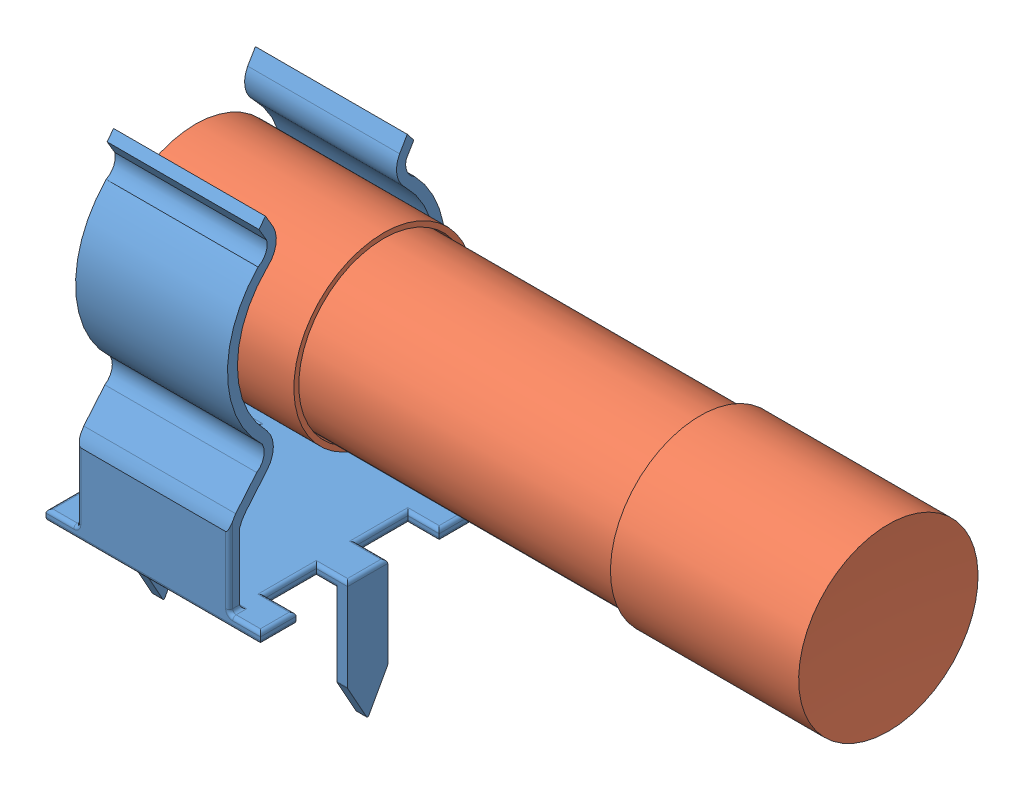
SolidWorks assembly SW3dPS-Full Fuse, configuration Default. Lengths in mm.
Overall size (21.01 12.9 6.2).
2 component instances, 2 part files, 3 mates.
Components (placement in the parent):
- SW3dPS-Full Fuse_Fuse Leg_2009-2: SW3dPS-Full Fuse_Fuse Leg_2009 [Default] at (-8 0 0) x (-1 0 0) z (0 1 0) size (6.1 6.2 12.9)
- SW3dPS-Full Fuse_Fuse Small 1A-1: SW3dPS-Full Fuse_Fuse Small 1A [Default] at (0 6.3 0) x (1 0 0) z (0 -1 0) size (19.91 5.21 5.19)
Mates (geometry in assembly coordinates):
- Coincident2: coincident aligned: plane of SW3dPS-Full Fuse_Fuse Small 1A-1; plane of assembly through (0 0 0) normal (1 0 0)
- Concentric2: concentric aligned: circle of SW3dPS-Full Fuse_Fuse Leg_2009-2; circle of SW3dPS-Full Fuse_Fuse Small 1A-1
- Coincident9: coincident aligned: plane of SW3dPS-Full Fuse_Fuse Small 1A-1 through (0 6.3 0) normal (0 0 1); plane of assembly through (0 0 0) normal (0 0 1)
